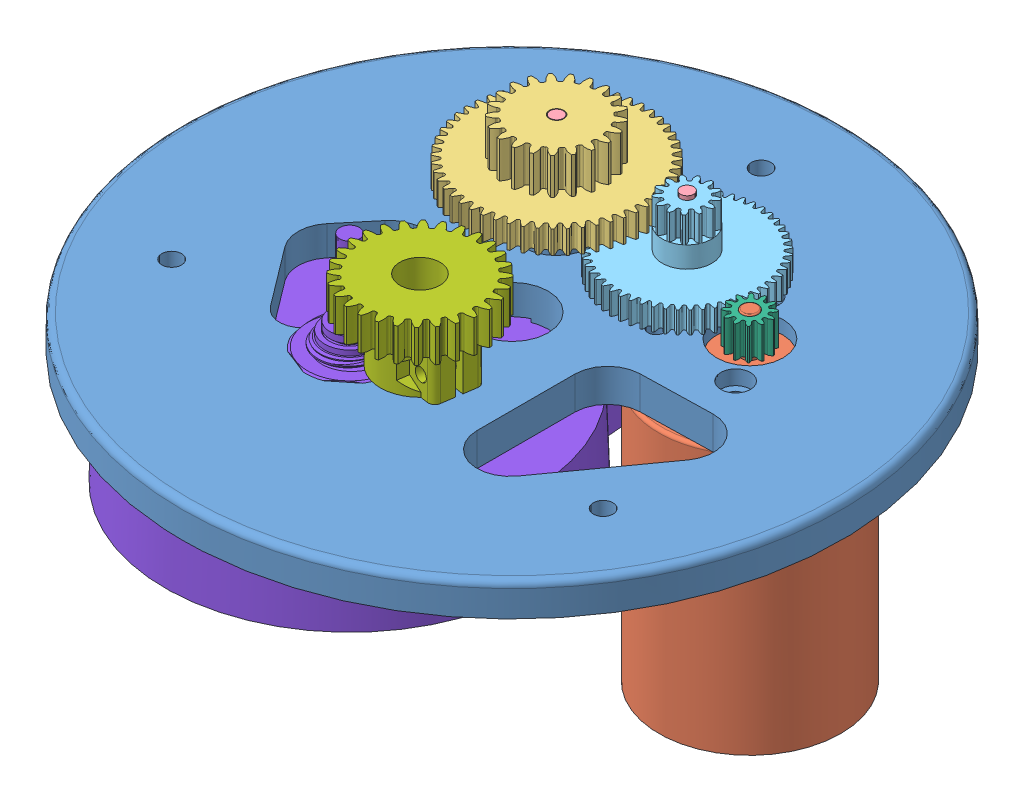
SolidWorks assembly motor_encoder_mount_v2, configuration Default. Lengths in mm.
Overall size (100 61.22 100).
9 component instances, 8 part files, 18 mates.
Components (placement in the parent):
- gear_plate_v2-1: gear_plate_v2 [Default] at (29.6826 29.2508 68.6333) size (100 11 100)
- motor-1: motor [Default] at (51.2418 -10.7492 54.1006) x (-0.558952 0 -0.8292) z (0.8292 0 -0.558952) size (27.6 49 27.6)
- gear2-1: gear2 [Default] at (22.1295 40.2508 54.3019) x (-0.767256 0 -0.641341) z (0 1 0) size (27 27 9)
- rod1-1: rod1 [Default] at (38.0033 30.2508 50.3849) x (0.295414 0 -0.955369) z (0.955369 0 0.295414) size (2 15 2)
- rod1-2: rod1 [Default] at (22.1295 34.2508 54.3019) x (-0.913157 0 0.407607) z (-0.407607 0 -0.913157) size (2 15 2)
- gear1-1: gear1 [Default] at (38.0033 34.2508 50.3849) x (-0.806349 0 -0.59144) z (0 1 0) size (22.68 22.68 10.4)
- gear0-2: gear0 [Default] at (51.2418 38.0508 54.1006) x (-0.207042 0 -0.978332) z (0 -1 0) size (6.16 6.16 4.8)
- gear3 v2-1: gear3 v2 [Default] at (33.8979 48.4692 86.8172) x (0.989255 0 0.146198) z (0 -1 0) size (20 20 12)
- S2-X-236-X-B-X-1: S2-X-236-X-B-X [.236 BB] at (22.1087 17.6938 85.6937) x (-0.996381 0 0.084995) z (-0.084995 0 -0.996381) size (55.96 32.66 66.51)
Mates (geometry in assembly coordinates):
- Concentric16: concentric anti-aligned: cylinder of gear_plate_v2-1 through (51.2418 24.2508 54.1006) axis (0 1 0) radius 5.05; cylinder of motor-1 through (51.2418 32.2508 54.1006) axis (0 -1 0) radius 5
- Concentric17: concentric anti-aligned: circle of gear_plate-1; cylinder of motor-1 through (42.745 32.2508 59.8281) axis (0 -1 0) radius 1.225
- Concentric18: concentric aligned: cylinder of gear_plate_v2-1 through (46.7702 24.2508 47.467) axis (0 1 0) radius 1.2; cylinder of motor-1 through (46.7702 26.2508 47.467) axis (0 1 0) radius 1
- Coincident20: coincident anti-aligned: plane of gear_plate_v2-1 through (29.6826 29.2508 68.6333) normal (0 -1 0); plane of motor-1 through (51.2418 29.2508 54.1006) normal (0 1 0)
- Coincident23: coincident anti-aligned: plane of gear_plate_v2-1 through (22.1295 40.2508 54.3019) normal (0 1 0); plane of gear2-1 through (22.1295 40.2508 54.3019) normal (0 -1 0)
- Concentric22: concentric anti-aligned: circle of gear_plate-1; cylinder of rod1-1 through (38.0033 45.2508 50.3849) axis (0 -1 0) radius 1
- Coincident25: coincident anti-aligned: plane of gear_plate_v2-1 through (29.6826 34.2508 68.6333) normal (0 1 0); plane of rod1-2 through (22.1295 34.2508 54.3019) normal (0 -1 0)
- Coincident26: coincident aligned: plane of gear_plate_v2-1 through (38.0033 30.2508 50.3849) normal (0 1 0); circle of rod1-1
- Coincident28: coincident anti-aligned: plane of gear_plate_v2-1 through (29.6826 34.2508 68.6333) normal (0 1 0); plane of gear1-1 through (38.0033 34.2508 50.3849) normal (0 -1 0)
- Distance1: distance = 1 mm anti-aligned: plane of gear0-2 through (48.4506 33.2508 53.345) normal (0 -1 0); plane of motor-1 through (51.2418 32.2508 54.1006) normal (0 1 0)
- GearMate2: gear = 52 : 12 mm: line of gear0-2 through (51.2418 33.2508 54.1006) axis (0 1 0); line of gear1-1 through (38.0033 44.6508 50.3849) axis (0 -1 0)
- Concentric27: concentric anti-aligned: cylinder of motor-1 through (51.2418 38.2508 54.1006) axis (0 -1 0) radius 1.25; cylinder of gear0-2 through (51.2418 33.2508 54.1006) axis (0 1 0) radius 1
- GearMate3: gear = 13 : 52 mm: line of gear2-1 through (22.1295 49.2508 54.3019) axis (0 -1 0); line of gear1-1 through (38.0033 40.7508 50.3849) axis (0 -1 0)
- Concentric28: concentric anti-aligned: cylinder of rod1-1 through (38.0033 45.2508 50.3849) axis (0 -1 0) radius 1; cylinder of gear1-1 through (38.0033 44.6508 50.3849) axis (0 1 0) radius 1
- Concentric29: concentric anti-aligned: cylinder of gear2-1 through (22.1295 52.2508 54.3019) axis (0 1 0) radius 1.1; cylinder of rod1-2 through (22.1295 49.2508 54.3019) axis (0 -1 0) radius 1
- Concentric30: concentric anti-aligned: circle of gear_plate-1; circle of gear2-1
- Coincident31: coincident anti-aligned: plane of gear_plate_v2-1 through (29.6826 29.2508 68.6333) normal (0 -1 0); plane of S2-X-236-X-B-X-1 through (22.1087 29.2508 85.6937) normal (0 1 0)
- Concentric33: concentric anti-aligned: cylinder of gear_plate_v2-1 through (22.1087 34.2508 85.6937) axis (0 -1 0) radius 5; cone of S2-X-236-X-B-X-1 through (22.1087 16.6778 85.6937) axis (0 1 0)
